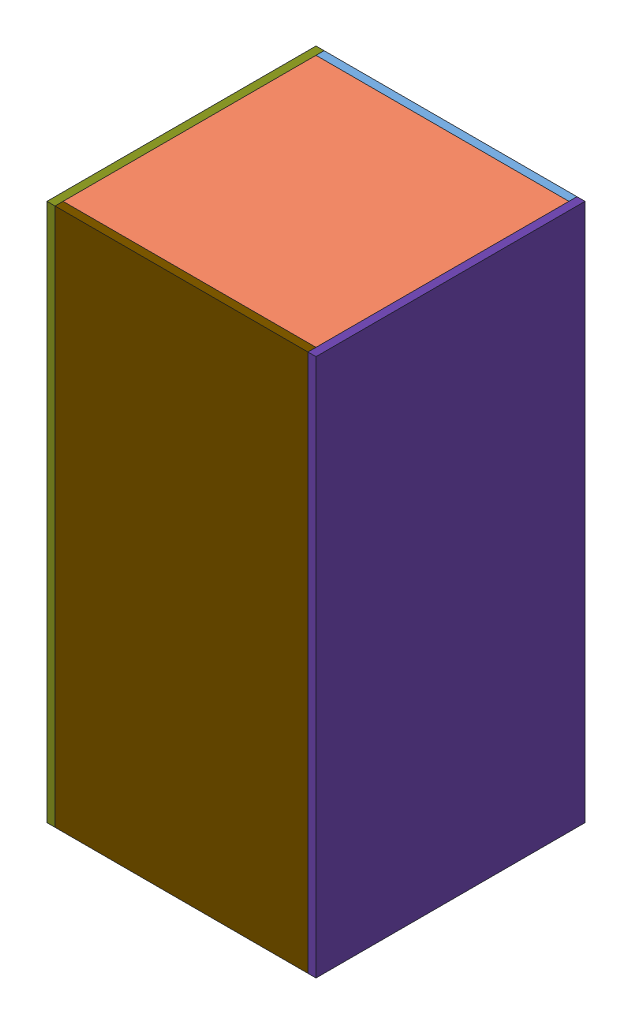
SolidWorks assembly Water_Detection_Payload_v9_with_Walls.step, configuration Default. Lengths in mm.
Overall size (100 200 100).
23 component instances, 20 part files, 0 mates.
Components (placement in the parent):
- M1050D1-Step v1.step-1: M1050D1-Step v1.step [Default] at (42 6.4266 46.9747) x (1 0 0) z (0 -1 0) size (22.02 21.78 4.05)
- M1050D1-Step v1.step-2: M1050D1-Step v1.step [Default] at (19 6.4266 45.9747) x (1 0 0) z (0 -1 0) size (22.02 21.78 4.05)
- M1050D1-Step v1.step-3: M1050D1-Step v1.step [Default] at (40 6.4266 23.9747) x (1 0 0) z (0 -1 0) size (22.02 21.78 4.05)
- SC0915 v1.step-1: SC0915 v1.step [Default] at (48.6 92 95.7) x (-1 0 0) z (0 -1 0) size (21 3.73 52.3)
- SC0915 v1.step-2: SC0915 v1.step [Default] at (75 3 40) size (21 3.73 52.3)
- CUI_DEVICES_CP60440 v1.step-1: CUI_DEVICES_CP60440 v1.step [Default] at (28.534 6.4899 35.0441) x (0 0 -1) z (0 1 0) size (40 80 4)
- (Unsaved).step-1: (Unsaved).step [Default] at origin size (28.49 23.5 21.35)
- (Unsaved)-0.step-1: (Unsaved)-0.step [Default] at origin size (6 18 6)
- (Unsaved)-1.step-1: (Unsaved)-1.step [Default] at origin size (28 95 28)
- (Unsaved)-2.step-1: (Unsaved)-2.step [Default] at origin size (21.75 13.85 21.75)
- (Unsaved)-3.step-1: (Unsaved)-3.step [Default] at origin size (45 105 5.28)
- (Unsaved)-4.step-1: (Unsaved)-4.step [Default] at origin size (6 25 25)
- (Unsaved)-5.step-1: (Unsaved)-5.step [Default] at origin size (25 25 6)
- (Unsaved)-6.step-1: (Unsaved)-6.step [Default] at origin size (36 29 36)
- (Unsaved)-7.step-1: (Unsaved)-7.step [Default] at origin size (25.68 25.52 6.85)
- (Unsaved)-8.step-1: (Unsaved)-8.step [Default] at origin size (25.4 5 25.4)
- (Unsaved)-9.step-1: (Unsaved)-9.step [Default] at origin size (94 3 94)
- (Unsaved)-10.step-1: (Unsaved)-10.step [Default] at origin size (40 20 40)
- (Unsaved)-11.step-1: (Unsaved)-11.step [Default] at origin size (3 200 100)
- (Unsaved)-12.step-1: (Unsaved)-12.step [Default] at origin size (3 200 100)
- (Unsaved)-13.step-1: (Unsaved)-13.step [Default] at origin size (94 200 3)
- (Unsaved)-14.step-1: (Unsaved)-14.step [Default] at origin size (94 200 3)
- (Unsaved)-15.step-1: (Unsaved)-15.step [Default] at origin size (94 3 94)
